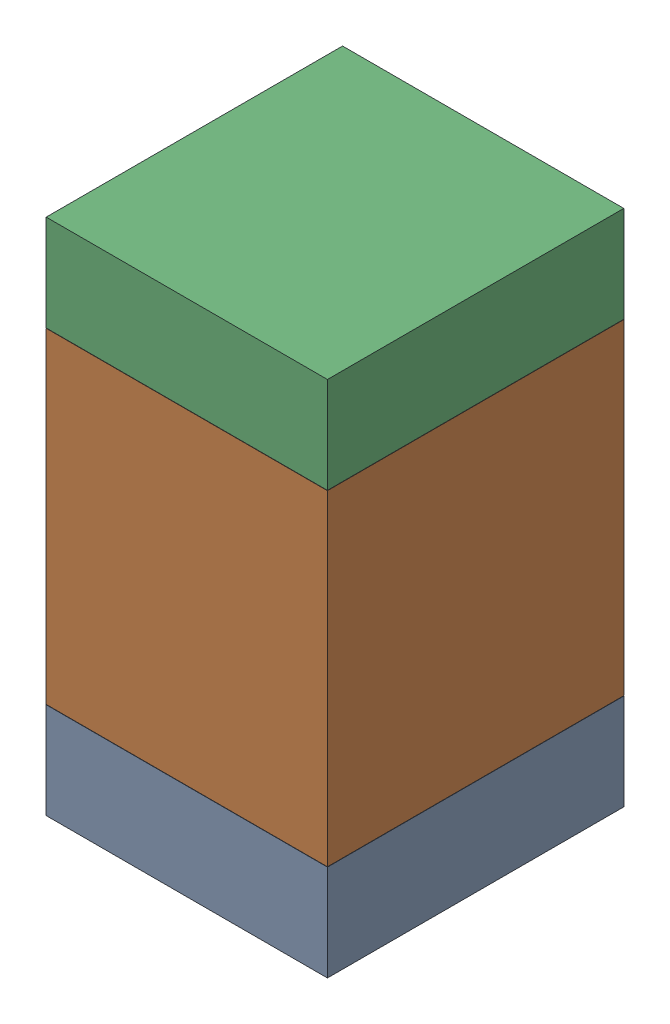
SolidWorks assembly R32, configuration Default. Lengths in mm.
Overall size (0.95 1.75 1).
6 component instances, 2 part files, 0 mates.
Components (placement in the parent):
- 6575495072-1: 6575495072 [Default] at (1.651 28.4975 0) size (0.95 0.32 1)
  - Extruded_6-1: Extruded_6 [Default] at origin size (0.95 0.32 1)
- 6575494912-1: 6575494912 [Default] at (1.651 29.21 0) size (0.95 1.1 1)
  - Extruded_7-1: Extruded_7 [Default] at origin size (0.95 1.1 1)
- 6575495072-2: 6575495072 [Default] at (1.651 29.9225 0) size (0.95 0.32 1)
  - Extruded_6-1: Extruded_6 [Default] at origin size (0.95 0.32 1)
